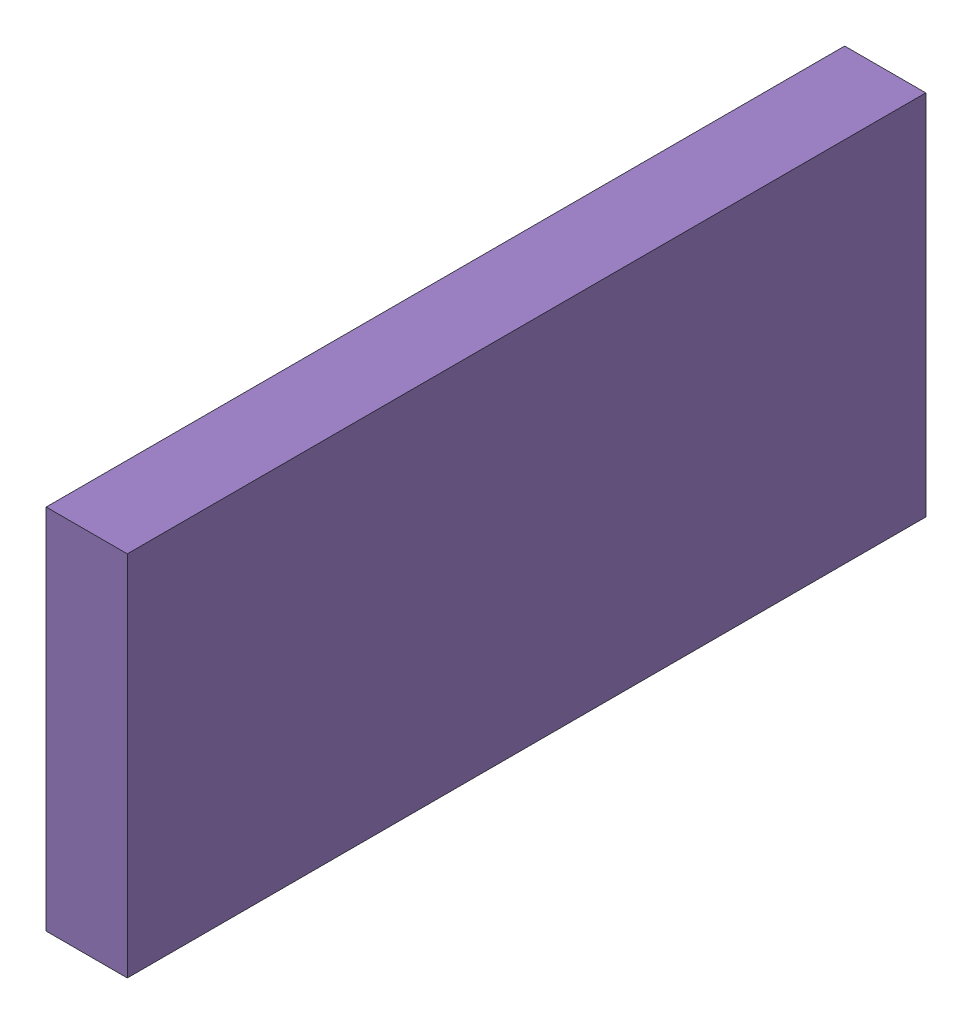
SolidWorks assembly C11, configuration Default. Lengths in mm.
Overall size (0.25 1.15 2.5).
22 component instances, 7 part files, 0 mates.
Components (placement in the parent):
- 6701982208-1:  [Default] at (27.7 14.8 0) (suppressed, hidden)
- 6327399040-1: 6327399040 [Default] at (4.2287 2.7675 -2.3606) x (0 0 -1) z (1 0 0) size (0.4 0.85 0.25)
  - 6701982208-1:  [Default] at (27.7 14.8 0) (suppressed, hidden)
  - Extruded-7-1: Extruded-7 [Default] at origin size (0.4 0.85 0.25)
- 6327399232-1: 6327399232 [Default] at (4.2287 2.7675 -2.3606) x (0 0 -1) z (1 0 0) size (1.75 0.95 0.25)
  - 6701982208-1:  [Default] at (27.7 14.8 0) (suppressed, hidden)
  - Extruded-8-1: Extruded-8 [Default] at origin size (1.75 0.95 0.25)
- 6327399424-1: 6327399424 [Default] at (4.2287 2.7675 -2.3606) x (0 0 -1) z (1 0 0) size (1.85 1.05 0.25)
  - 6701982208-1:  [Default] at (27.7 14.8 0) (suppressed, hidden)
  - Extruded-9-1: Extruded-9 [Default] at origin size (1.85 1.05 0.25)
- 6327399616-1: 6327399616 [Default] at (4.2287 2.7675 -2.3606) x (0 0 -1) z (1 0 0) size (2.4 1.05 0.25)
  - 6701982208-1:  [Default] at (27.7 14.8 0) (suppressed, hidden)
  - Extruded-10-1: Extruded-10 [Default] at origin size (2.4 1.05 0.25)
- 6327399808-1: 6327399808 [Default] at (4.2287 2.7675 -2.3606) x (0 0 -1) z (1 0 0) size (2.5 1.15 0.25)
  - 6701982208-1:  [Default] at (27.7 14.8 0) (suppressed, hidden)
  - Extruded-11-1: Extruded-11 [Default] at origin size (2.5 1.15 0.25)
- 6327400000-1: 6327400000 [Default] at (4.2287 2.7675 -2.3606) x (0 0 -1) z (1 0 0) size (2.4 1.05 0.25)
  - 6701982208-1:  [Default] at (27.7 14.8 0) (suppressed, hidden)
  - Extruded-12-1: Extruded-12 [Default] at origin size (2.4 1.05 0.25)
- 6327400960-1: 6327400960 [Default] at (4.2287 2.7675 -2.3606) x (0 0 -1) z (1 0 0) size (0.95 0.95 0.25)
  - 6701982208-1:  [Default] at (27.7 14.8 0) (suppressed, hidden)
  - Extruded-14-1: Extruded-14 [Default] at origin size (0.95 0.95 0.25)
